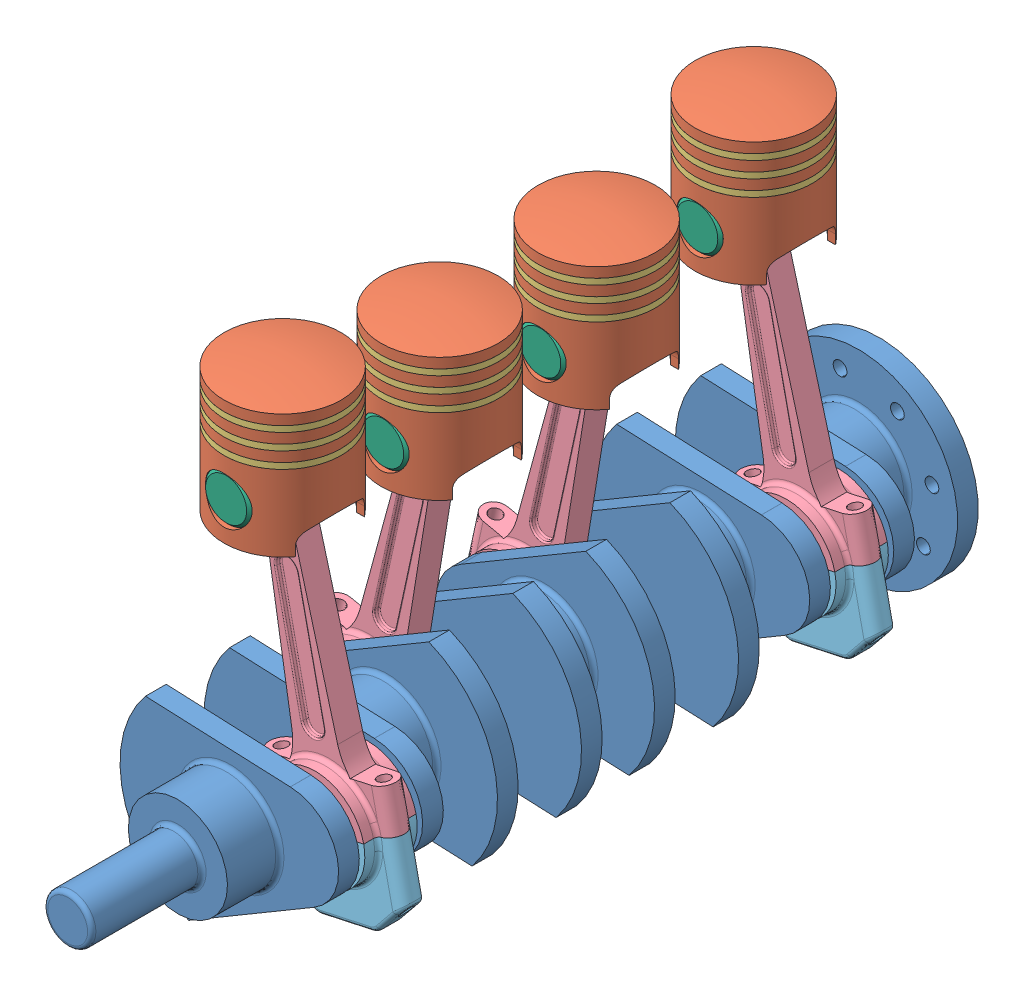
SolidWorks assembly Four Cylinder Engine Assembly, configuration Default. Lengths in mm.
Overall size (5148.25 9259.9 14960.6).
29 component instances, 6 part files, 69 mates.
Components (placement in the parent):
- 3rd CrankShaft-1: 3rd CrankShaft [Default] at (0 1060.8829 606257.2199) x (-0.242705 0.9701 0) z (0 0 1) size (3657.6 4064 14960.6)
- 1st Piston-1: 1st Piston [Default] at (0 5640.4819 605673.0199) size (2159 2413 2159)
- 2nd Piston Ring-1: 2nd Piston Ring [Default] at (0 7631.8419 605673.0199) x (1 0 0.000107) z (-0.000107 0 1) size (2159 109.22 2159)
- 4th Connecting Rod-1: 4th Connecting Rod [Default] at (0 6326.2819 605673.0199) x (0.977237 0.212149 0) z (0 0 1) size (2387.6 5681.98 965.2)
- 5th Connecting Rod Cap-1: 5th Connecting Rod Cap [Default] at (1084.1839 1332.1302 605673.0199) x (-0.977237 -0.212149 0) z (0 0 1) size (2387.6 1524 965.2)
- 6th Piston Pin-1: 6th Piston Pin [Default] at (0 6326.2819 605673.0199) size (858.52 858.52 2082.8)
- 2nd Piston Ring-10: 2nd Piston Ring [Default] at (0 7337.2019 605673.0199) x (0.547034 0 -0.83711) z (0.83711 0 0.547034) size (2159 109.22 2159)
- 2nd Piston Ring-12: 2nd Piston Ring [Default] at (0 7042.5619 605673.0199) x (0.547034 0 -0.83711) z (0.83711 0 0.547034) size (2159 109.22 2159)
- 1st Piston-11: 1st Piston [Default] at (0 5097.9872 602777.4199) size (2159 2413 2159)
- 2nd Piston Ring-26: 2nd Piston Ring [Default] at (0 7089.3472 602777.4199) x (0.941494 0 -0.33703) z (0.33703 0 0.941494) size (2159 109.22 2159)
- 2nd Piston Ring-27: 2nd Piston Ring [Default] at (0 6794.7072 602777.4199) x (0.232794 0 -0.972526) z (0.972526 0 0.232794) size (2159 109.22 2159)
- 2nd Piston Ring-28: 2nd Piston Ring [Default] at (0 6500.0672 602777.4199) x (0.232794 0 -0.972526) z (0.972526 0 0.232794) size (2159 109.22 2159)
- 6th Piston Pin-6: 6th Piston Pin [Default] at (0 5783.7872 602777.4199) x (0.216826 -0.97621 0) z (0 0 1) size (858.52 858.52 2082.8)
- 4th Connecting Rod-6: 4th Connecting Rod [Default] at (0 5783.7872 602777.4199) x (0.977237 -0.212149 0) z (0 0 1) size (2387.6 5681.98 965.2)
- 5th Connecting Rod Cap-6: 5th Connecting Rod Cap [Default] at (-1084.1839 789.6355 602777.4199) x (-0.977237 0.212149 0) z (0 0 1) size (2387.6 1524 965.2)
- 1st Piston-13: 1st Piston [Default] at (0 5097.9872 599881.8199) x (-1 0 0) z (0 0 -1) size (2159 2413 2159)
- 2nd Piston Ring-32: 2nd Piston Ring [Default] at (0 7089.3472 599881.8199) x (0.790612 0 -0.612318) z (0.612318 0 0.790612) size (2159 109.22 2159)
- 2nd Piston Ring-33: 2nd Piston Ring [Default] at (0 6794.7072 599881.8199) x (-0.080193 0 -0.996779) z (0.996779 0 -0.080193) size (2159 109.22 2159)
- 2nd Piston Ring-34: 2nd Piston Ring [Default] at (0 6500.0672 599881.8199) x (-0.080193 0 -0.996779) z (0.996779 0 -0.080193) size (2159 109.22 2159)
- 6th Piston Pin-8: 6th Piston Pin [Default] at (0 5783.7872 599881.8199) x (-0.34202 0.939693 0) z (0 0 -1) size (858.52 858.52 2082.8)
- 4th Connecting Rod-8: 4th Connecting Rod [Default] at (0 5783.7872 599881.8199) x (-0.977237 0.212149 0) z (0 0 -1) size (2387.6 5681.98 965.2)
- 5th Connecting Rod Cap-8: 5th Connecting Rod Cap [Default] at (-1084.1839 789.6355 599881.8199) x (0.977237 -0.212149 0) z (0 0 -1) size (2387.6 1524 965.2)
- 1st Piston-15: 1st Piston [Default] at (0 5640.4819 596986.2199) x (-1 0 0) z (0 0 -1) size (2159 2413 2159)
- 2nd Piston Ring-38: 2nd Piston Ring [Default] at (0 7631.8419 596986.2199) x (0.600086 0 -0.799936) z (0.799936 0 0.600086) size (2159 109.22 2159)
- 2nd Piston Ring-39: 2nd Piston Ring [Default] at (0 7337.2019 596986.2199) x (-0.341468 0 -0.939893) z (0.939893 0 -0.341468) size (2159 109.22 2159)
- 2nd Piston Ring-40: 2nd Piston Ring [Default] at (0 7042.5619 596986.2199) x (-0.341468 0 -0.939893) z (0.939893 0 -0.341468) size (2159 109.22 2159)
- 6th Piston Pin-10: 6th Piston Pin [Default] at (0 6326.2819 596986.2199) x (-0.5 0.866025 0) z (0 0 -1) size (858.52 858.52 2082.8)
- 4th Connecting Rod-10: 4th Connecting Rod [Default] at (0 6326.2819 596986.2199) x (-0.977237 -0.212149 0) z (0 0 -1) size (2387.6 5681.98 965.2)
- 5th Connecting Rod Cap-10: 5th Connecting Rod Cap [Default] at (1084.1839 1332.1302 596986.2199) x (0.977237 0.212149 0) z (0 0 -1) size (2387.6 1524 965.2)
Mates (geometry in assembly coordinates):
- Concentric3: concentric aligned: cylinder of 3rd CrankShaft-1 through (0 1060.8829 609635.4199) axis (0 0 -1) radius 444.5
- Coincident5: coincident aligned: plane of 1st Piston-1 through (0 5640.4819 605673.0199) normal (0 0 1); plane of 6th Piston Pin-1 through (0 6326.2819 605673.0199) normal (0 0 1)
- Concentric4: concentric anti-aligned: cylinder of 1st Piston-1 through (0 6326.2819 604593.5199) axis (0 0 1) radius 429.26; cylinder of 6th Piston Pin-1 through (0 6326.2819 606714.4199) axis (0 0 -1) radius 429.26
- Concentric10: concentric aligned: cylinder of 1st Piston-1 through (0 7926.4819 605673.0199) axis (0 -1 0) radius 1079.5; cylinder of 2nd Piston Ring-1 through (0 7741.0619 605673.0199) axis (0 -1 0) radius 1079.5
- Coincident6: coincident anti-aligned: plane of 1st Piston-1 through (0 7631.8419 605673.0199) normal (0 1 0); plane of 2nd Piston Ring-1 through (0 7631.8419 605673.0199) normal (0 -1 0)
- Concentric15: concentric anti-aligned: cylinder of 1st Piston-1 through (0 7337.2019 605673.0199) axis (0 1 0) radius 1003.3; cylinder of 2nd Piston Ring-10 through (0 7446.4219 605673.0199) axis (0 -1 0) radius 1079.5
- Coincident10: coincident anti-aligned: plane of 1st Piston-1 through (0 7337.2019 605673.0199) normal (0 1 0); plane of 2nd Piston Ring-10 through (0 7337.2019 605673.0199) normal (0 -1 0)
- Concentric16: concentric anti-aligned: cylinder of 1st Piston-1 through (0 7042.5619 605673.0199) axis (0 1 0) radius 1003.3; cylinder of 2nd Piston Ring-12 through (0 7151.7819 605673.0199) axis (0 -1 0) radius 1079.5
- Coincident11: coincident anti-aligned: plane of 1st Piston-1 through (0 7042.5619 605673.0199) normal (0 1 0); plane of 2nd Piston Ring-12 through (0 7042.5619 605673.0199) normal (0 -1 0)
- Coincident12: coincident aligned: plane of 1st Piston-1 through (0 5640.4819 605673.0199) normal (0 0 1); plane of 4th Connecting Rod-1 through (0 6326.2819 605673.0199) normal (0 0 1)
- Concentric17: concentric aligned: cylinder of 4th Connecting Rod-1 through (0 6326.2819 606155.6199) axis (0 0 -1) radius 429.26; cylinder of 6th Piston Pin-1 through (0 6326.2819 606714.4199) axis (0 0 -1) radius 429.26
- Concentric19: concentric aligned: cylinder of 4th Connecting Rod-1 through (2027.4133 1536.8966 605673.0199) axis (-0.212149 0.977237 0) radius 114.3; cylinder of 5th Connecting Rod Cap-1 through (2350.7286 47.5869 605673.0199) axis (-0.212149 0.977237 0) radius 114.3
- Concentric20: concentric aligned: cylinder of 4th Connecting Rod-1 through (2027.4133 1536.8966 605673.0199) axis (-0.212149 0.977237 0) radius 114.3; cylinder of 5th Connecting Rod Cap-1 through (2350.7286 47.5869 605673.0199) axis (-0.212149 0.977237 0) radius 114.3
- Coincident13: coincident anti-aligned: plane of 4th Connecting Rod-1 through (1084.1839 1332.1302 606155.6199) normal (0.212149 -0.977237 0); plane of 5th Connecting Rod Cap-1 through (1977.7696 1526.1194 606155.6199) normal (-0.212149 0.977237 0)
- Width1: width anti-aligned: plane of 3rd CrankShaft-1 through (0 1060.8829 605088.8199) normal (0 0 1); plane of 4th Connecting Rod-1 through (0 1060.8829 606257.2199) normal (0 0 -1); plane of 3rd CrankShaft-1 through (0 6326.2819 605444.4199) normal (0 0 -1); plane of 4th Connecting Rod-1 through (0 6326.2819 605901.6199) normal (0 0 1)
- Concentric21: concentric anti-aligned: cylinder of 3rd CrankShaft-1 through (1084.1839 1332.1302 605088.8199) axis (0 0 1) radius 685.8; cylinder of 5th Connecting Rod Cap-1 through (1084.1839 1332.1302 606155.6199) axis (0 0 -1) radius 685.8
- Concentric22: concentric anti-aligned: cylinder of 1st Piston-1 through (0 7926.4819 605673.0199) axis (0 -1 0) radius 1079.5
- Coincident39: coincident aligned: circle of 4th Connecting Rod-1; circle of 5th Connecting Rod Cap-1
- Coincident40: coincident aligned: plane of 1st Piston-11 through (0 5097.9872 602777.4199) normal (0 0 1); plane of 6th Piston Pin-6 through (0 5783.7872 602777.4199) normal (0 0 1)
- Concentric54: concentric anti-aligned: cylinder of 1st Piston-11 through (0 5783.7872 601697.9199) axis (0 0 1) radius 429.26; cylinder of 6th Piston Pin-6 through (0 5783.7872 603818.8199) axis (0 0 -1) radius 429.26
- Concentric55: concentric aligned: cylinder of 1st Piston-11 through (0 7383.9872 602777.4199) axis (0 -1 0) radius 1079.5; cylinder of 2nd Piston Ring-26 through (0 7198.5672 602777.4199) axis (0 -1 0) radius 1079.5
- Coincident41: coincident anti-aligned: plane of 1st Piston-11 through (0 7089.3472 602777.4199) normal (0 1 0); plane of 2nd Piston Ring-26 through (0 7089.3472 602777.4199) normal (0 -1 0)
- Concentric56: concentric anti-aligned: cylinder of 1st Piston-11 through (0 6794.7072 602777.4199) axis (0 1 0) radius 1003.3; cylinder of 2nd Piston Ring-27 through (0 6903.9272 602777.4199) axis (0 -1 0) radius 1079.5
- Coincident42: coincident anti-aligned: plane of 1st Piston-11 through (0 6794.7072 602777.4199) normal (0 1 0); plane of 2nd Piston Ring-27 through (0 6794.7072 602777.4199) normal (0 -1 0)
- Concentric57: concentric anti-aligned: cylinder of 1st Piston-11 through (0 6500.0672 602777.4199) axis (0 1 0) radius 1003.3; cylinder of 2nd Piston Ring-28 through (0 6609.2872 602777.4199) axis (0 -1 0) radius 1079.5
- Coincident43: coincident anti-aligned: plane of 1st Piston-11 through (0 6500.0672 602777.4199) normal (0 1 0); plane of 2nd Piston Ring-28 through (0 6500.0672 602777.4199) normal (0 -1 0)
- Coincident44: coincident aligned: plane of 1st Piston-11 through (0 5097.9872 602777.4199) normal (0 0 1); plane of 4th Connecting Rod-6 through (0 5783.7872 602777.4199) normal (0 0 1)
- Concentric58: concentric aligned: cylinder of 6th Piston Pin-6 through (0 5783.7872 603818.8199) axis (0 0 -1) radius 429.26; cylinder of 4th Connecting Rod-6 through (0 5783.7872 603260.0199) axis (0 0 -1) radius 429.26
- Concentric59: concentric aligned: cylinder of 4th Connecting Rod-6 through (-140.9544 584.8692 602777.4199) axis (0.212149 0.977237 0) radius 114.3; cylinder of 5th Connecting Rod Cap-6 through (-464.2697 -904.4405 602777.4199) axis (0.212149 0.977237 0) radius 114.3
- Concentric60: concentric aligned: cylinder of 4th Connecting Rod-6 through (-140.9544 584.8692 602777.4199) axis (0.212149 0.977237 0) radius 114.3; cylinder of 5th Connecting Rod Cap-6 through (-464.2697 -904.4405 602777.4199) axis (0.212149 0.977237 0) radius 114.3
- Coincident45: coincident anti-aligned: plane of 4th Connecting Rod-6 through (-1084.1839 789.6355 603260.0199) normal (-0.212149 -0.977237 0); plane of 5th Connecting Rod Cap-6 through (-190.5981 595.6464 603260.0199) normal (0.212149 0.977237 0)
- Coincident46: coincident aligned: circle of 4th Connecting Rod-6; circle of 5th Connecting Rod Cap-6
- Width5: width anti-aligned: plane of 3rd CrankShaft-1 through (0 1060.8829 603361.6199) normal (0 0 -1); plane of 4th Connecting Rod-6 through (0 1060.8829 602193.2199) normal (0 0 1); plane of 3rd CrankShaft-1 through (0 5783.7872 602548.8199) normal (0 0 -1); plane of 4th Connecting Rod-6 through (0 5783.7872 603006.0199) normal (0 0 1)
- Concentric61: concentric anti-aligned: cylinder of 3rd CrankShaft-1 through (-1084.1839 789.6355 602193.2199) axis (0 0 1) radius 685.8; cylinder of 5th Connecting Rod Cap-6 through (-1084.1839 789.6355 603260.0199) axis (0 0 -1) radius 685.8
- Concentric62: concentric anti-aligned: cylinder of 1st Piston-11 through (0 7383.9872 602777.4199) axis (0 -1 0) radius 1079.5
- Coincident54: coincident aligned: plane of 1st Piston-13 through (0 5097.9872 599881.8199) normal (0 0 -1); plane of 6th Piston Pin-8 through (0 5783.7872 599881.8199) normal (0 0 -1)
- Concentric70: concentric anti-aligned: cylinder of 1st Piston-13 through (0 5783.7872 600961.3199) axis (0 0 -1) radius 429.26; cylinder of 6th Piston Pin-8 through (0 5783.7872 598840.4199) axis (0 0 1) radius 429.26
- Concentric71: concentric aligned: cylinder of 1st Piston-13 through (0 7383.9872 599881.8199) axis (0 -1 0) radius 1079.5; cylinder of 2nd Piston Ring-32 through (0 7198.5672 599881.8199) axis (0 -1 0) radius 1079.5
- Coincident55: coincident anti-aligned: plane of 1st Piston-13 through (0 7089.3472 599881.8199) normal (0 1 0); plane of 2nd Piston Ring-32 through (0 7089.3472 599881.8199) normal (0 -1 0)
- Concentric72: concentric anti-aligned: cylinder of 1st Piston-13 through (0 6794.7072 599881.8199) axis (0 1 0) radius 1003.3; cylinder of 2nd Piston Ring-33 through (0 6903.9272 599881.8199) axis (0 -1 0) radius 1079.5
- Coincident56: coincident anti-aligned: plane of 1st Piston-13 through (0 6794.7072 599881.8199) normal (0 1 0); plane of 2nd Piston Ring-33 through (0 6794.7072 599881.8199) normal (0 -1 0)
- Concentric73: concentric anti-aligned: cylinder of 1st Piston-13 through (0 6500.0672 599881.8199) axis (0 1 0) radius 1003.3; cylinder of 2nd Piston Ring-34 through (0 6609.2872 599881.8199) axis (0 -1 0) radius 1079.5
- Coincident57: coincident anti-aligned: plane of 1st Piston-13 through (0 6500.0672 599881.8199) normal (0 1 0); plane of 2nd Piston Ring-34 through (0 6500.0672 599881.8199) normal (0 -1 0)
- Coincident58: coincident aligned: plane of 1st Piston-13 through (0 5097.9872 599881.8199) normal (0 0 -1); plane of 4th Connecting Rod-8 through (0 5783.7872 599881.8199) normal (0 0 -1)
- Concentric74: concentric aligned: cylinder of 6th Piston Pin-8 through (0 5783.7872 598840.4199) axis (0 0 1) radius 429.26; cylinder of 4th Connecting Rod-8 through (0 5783.7872 599399.2199) axis (0 0 1) radius 429.26
- Concentric75: concentric aligned: cylinder of 4th Connecting Rod-8 through (-2027.4133 994.4019 599881.8199) axis (0.212149 0.977237 0) radius 114.3; cylinder of 5th Connecting Rod Cap-8 through (-2350.7286 -494.9078 599881.8199) axis (0.212149 0.977237 0) radius 114.3
- Concentric76: concentric aligned: cylinder of 4th Connecting Rod-8 through (-2027.4133 994.4019 599881.8199) axis (0.212149 0.977237 0) radius 114.3; cylinder of 5th Connecting Rod Cap-8 through (-2350.7286 -494.9078 599881.8199) axis (0.212149 0.977237 0) radius 114.3
- Coincident59: coincident anti-aligned: plane of 4th Connecting Rod-8 through (-1084.1839 789.6355 599399.2199) normal (-0.212149 -0.977237 0); plane of 5th Connecting Rod Cap-8 through (-1977.7696 983.6247 599399.2199) normal (0.212149 0.977237 0)
- Coincident60: coincident aligned: circle of 4th Connecting Rod-8; circle of 5th Connecting Rod Cap-8
- Width6: width anti-aligned: plane of 3rd CrankShaft-1 through (0 1060.8829 600466.0199) normal (0 0 -1); plane of 4th Connecting Rod-8 through (0 1060.8829 599297.6199) normal (0 0 1); plane of 3rd CrankShaft-1 through (0 5783.7872 600110.4199) normal (0 0 1); plane of 4th Connecting Rod-8 through (0 5783.7872 599653.2199) normal (0 0 -1)
- Concentric77: concentric anti-aligned: cylinder of 3rd CrankShaft-1 through (-1084.1839 789.6355 600466.0199) axis (0 0 -1) radius 685.8; cylinder of 5th Connecting Rod Cap-8 through (-1084.1839 789.6355 599399.2199) axis (0 0 1) radius 685.8
- Concentric78: concentric anti-aligned: cylinder of 1st Piston-13 through (0 7383.9872 599881.8199) axis (0 -1 0) radius 1079.5
- Coincident68: coincident aligned: plane of 1st Piston-15 through (0 5640.4819 596986.2199) normal (0 0 -1); plane of 6th Piston Pin-10 through (0 6326.2819 596986.2199) normal (0 0 -1)
- Concentric86: concentric anti-aligned: cylinder of 1st Piston-15 through (0 6326.2819 598065.7199) axis (0 0 -1) radius 429.26; cylinder of 6th Piston Pin-10 through (0 6326.2819 595944.8199) axis (0 0 1) radius 429.26
- Concentric87: concentric aligned: cylinder of 1st Piston-15 through (0 7926.4819 596986.2199) axis (0 -1 0) radius 1079.5; cylinder of 2nd Piston Ring-38 through (0 7741.0619 596986.2199) axis (0 -1 0) radius 1079.5
- Coincident69: coincident anti-aligned: plane of 1st Piston-15 through (0 7631.8419 596986.2199) normal (0 1 0); plane of 2nd Piston Ring-38 through (0 7631.8419 596986.2199) normal (0 -1 0)
- Concentric88: concentric anti-aligned: cylinder of 1st Piston-15 through (0 7337.2019 596986.2199) axis (0 1 0) radius 1003.3; cylinder of 2nd Piston Ring-39 through (0 7446.4219 596986.2199) axis (0 -1 0) radius 1079.5
- Coincident70: coincident anti-aligned: plane of 1st Piston-15 through (0 7337.2019 596986.2199) normal (0 1 0); plane of 2nd Piston Ring-39 through (0 7337.2019 596986.2199) normal (0 -1 0)
- Concentric89: concentric anti-aligned: cylinder of 1st Piston-15 through (0 7042.5619 596986.2199) axis (0 1 0) radius 1003.3; cylinder of 2nd Piston Ring-40 through (0 7151.7819 596986.2199) axis (0 -1 0) radius 1079.5
- Coincident71: coincident anti-aligned: plane of 1st Piston-15 through (0 7042.5619 596986.2199) normal (0 1 0); plane of 2nd Piston Ring-40 through (0 7042.5619 596986.2199) normal (0 -1 0)
- Coincident72: coincident aligned: plane of 1st Piston-15 through (0 5640.4819 596986.2199) normal (0 0 -1); plane of 4th Connecting Rod-10 through (0 6326.2819 596986.2199) normal (0 0 -1)
- Concentric90: concentric aligned: cylinder of 6th Piston Pin-10 through (0 6326.2819 595944.8199) axis (0 0 1) radius 429.26; cylinder of 4th Connecting Rod-10 through (0 6326.2819 596503.6199) axis (0 0 1) radius 429.26
- Concentric91: concentric aligned: cylinder of 4th Connecting Rod-10 through (140.9544 1127.3639 596986.2199) axis (-0.212149 0.977237 0) radius 114.3; cylinder of 5th Connecting Rod Cap-10 through (464.2697 -361.9458 596986.2199) axis (-0.212149 0.977237 0) radius 114.3
- Concentric92: concentric aligned: cylinder of 4th Connecting Rod-10 through (140.9544 1127.3639 596986.2199) axis (-0.212149 0.977237 0) radius 114.3; cylinder of 5th Connecting Rod Cap-10 through (464.2697 -361.9458 596986.2199) axis (-0.212149 0.977237 0) radius 114.3
- Coincident73: coincident anti-aligned: plane of 4th Connecting Rod-10 through (1084.1839 1332.1302 596503.6199) normal (0.212149 -0.977237 0); plane of 5th Connecting Rod Cap-10 through (190.5981 1138.1411 596503.6199) normal (-0.212149 0.977237 0)
- Coincident74: coincident aligned: circle of 4th Connecting Rod-10; circle of 5th Connecting Rod Cap-10
- Width7: width anti-aligned: plane of 3rd CrankShaft-1 through (0 1060.8829 597570.4199) normal (0 0 -1); plane of 4th Connecting Rod-10 through (0 1060.8829 596402.0199) normal (0 0 1); plane of 3rd CrankShaft-1 through (0 6326.2819 597214.8199) normal (0 0 1); plane of 4th Connecting Rod-10 through (0 6326.2819 596757.6199) normal (0 0 -1)
- Concentric93: concentric anti-aligned: cylinder of 3rd CrankShaft-1 through (1084.1839 1332.1302 597570.4199) axis (0 0 -1) radius 685.8; cylinder of 5th Connecting Rod Cap-10 through (1084.1839 1332.1302 596503.6199) axis (0 0 1) radius 685.8
- Concentric94: concentric anti-aligned: cylinder of 1st Piston-15 through (0 7926.4819 596986.2199) axis (0 -1 0) radius 1079.5
